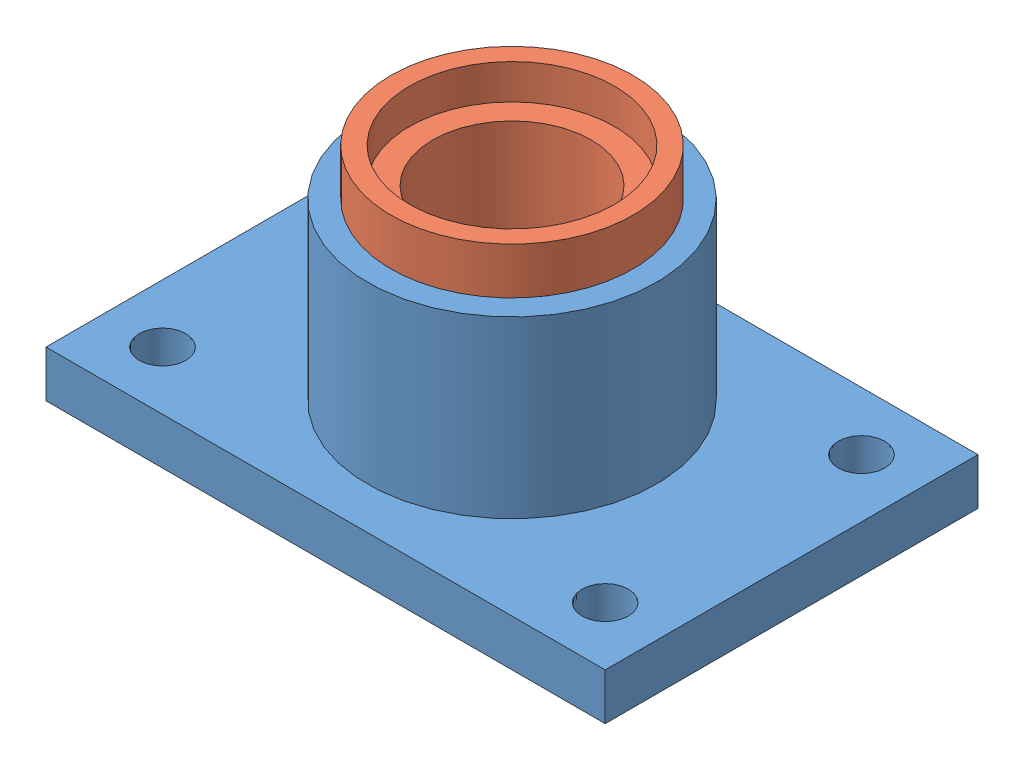
SolidWorks assembly Assem1, configuration Default. Lengths in mm.
Overall size (240 115 160).
3 component instances, 3 part files, 4 mates.
Components (placement in the parent):
- Base-1: Base [Default] at (95.4723 66.0081 221.359) size (240 95 160)
- Bush-1: Bush [Default] at (95.4723 86.0081 221.359) x (0.714218 0 0.699923) z (-0.699923 0 0.714218) size (104 95 104)
- Pad-1: Pad [Default] at (95.4723 86.0081 221.359) size (68 15 68)
Mates (geometry in assembly coordinates):
- Concentric1: concentric anti-aligned: cylinder of Base-1 through (95.4723 35.5805 221.359) axis (0 -1 0) radius 49.5; cylinder of Bush-1 through (95.4723 160.8088 221.359) axis (0 1 0) radius 46.5
- Coincident3: coincident anti-aligned: plane of Base-1 through (143.4723 161.0081 221.359) normal (0 1 0); plane of Bush-1 through (129.7548 161.0081 254.9553) normal (0 -1 0)
- Coincident5: coincident anti-aligned: circle of Base-1; circle of Pad-1
- Concentric5: concentric anti-aligned: cylinder of Bush-1 through (95.4723 160.8088 221.359) axis (0 1 0) radius 34; cylinder of Pad-1 through (95.4723 101.0081 221.359) axis (0 -1 0) radius 34
